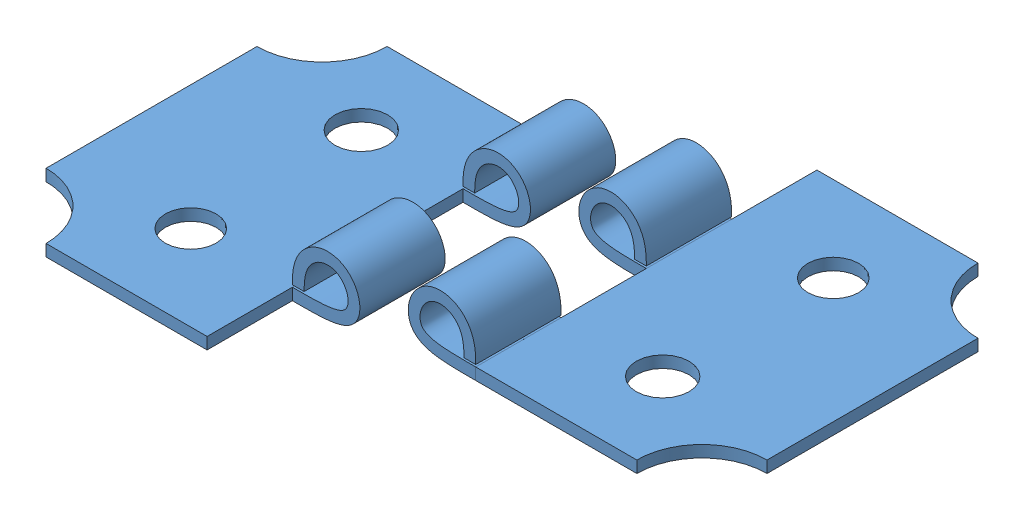
SolidWorks assembly Hinge, configuration Default. Lengths in mm.
Overall size (33.82 8.04 24.62).
3 component instances, 2 part files, 1 mates.
Components (placement in the parent):
- HingeSide-1: HingeSide [Default] at (-2.2381 -4.7175 -0.6193) size (13.95 2.98 16)
- HingeSide-2: HingeSide [Default] at (7.3082 0.3427 -0.6187) x (-1 0 0) z (0 0 -1) size (13.95 2.98 16)
- Spindle-1: Spindle [Default] at origin size (1.5 1.5 16)
Mates (geometry in assembly coordinates):
- Coincident5: coincident anti-aligned: plane of HingeSide-1 through (-2.2379 -4.1675 -4.6193) normal (-0.00006 0 1); plane of HingeSide-2 through (7.3084 0.8927 -4.6187) normal (0.00006 0 -1)
